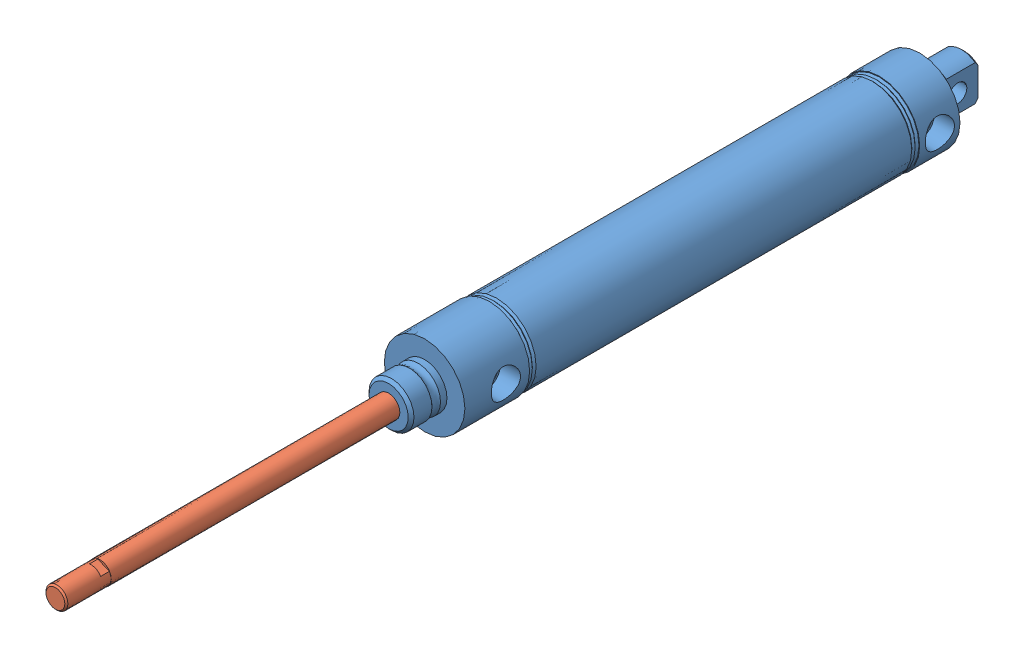
SolidWorks assembly A17040DP, configuration Default. Lengths in mm.
Overall size (33.2 33.2 320.8).
2 component instances, 2 part files, 2 mates.
Components (placement in the parent):
- A17040DP-MainBody-1: A17040DP-MainBody [Default] at (-30.1135 49.4561 14.6128) x (0 0 -1) z (1 0 0) size (203.2 28.45 28.45)
- Part13-1: Part13 [Default] at (-30.1135 49.4561 862.0167) x (0 0 -1) z (-0.963937 0.266129 0) size (172.97 26.99 26.99)
Mates (geometry in assembly coordinates):
- Concentric2: concentric: cylinder of A17040DP-MainBody-1 through (-30.1135 49.4561 14.6128) axis (0 0 -1) radius 3.9624; cylinder of Part13-1 through (-30.1135 49.4561 -31.1072) axis (0 0 1) radius 3.9624
- LimitDistance2: limit distance = 132.08 mm: plane of Part13-1 through (-30.1135 49.4561 -43.8072) normal (0 0 -1); plane of A17040DP-MainBody-1 through (-30.1135 57.3618 -175.8872) normal (0 0 -1)
